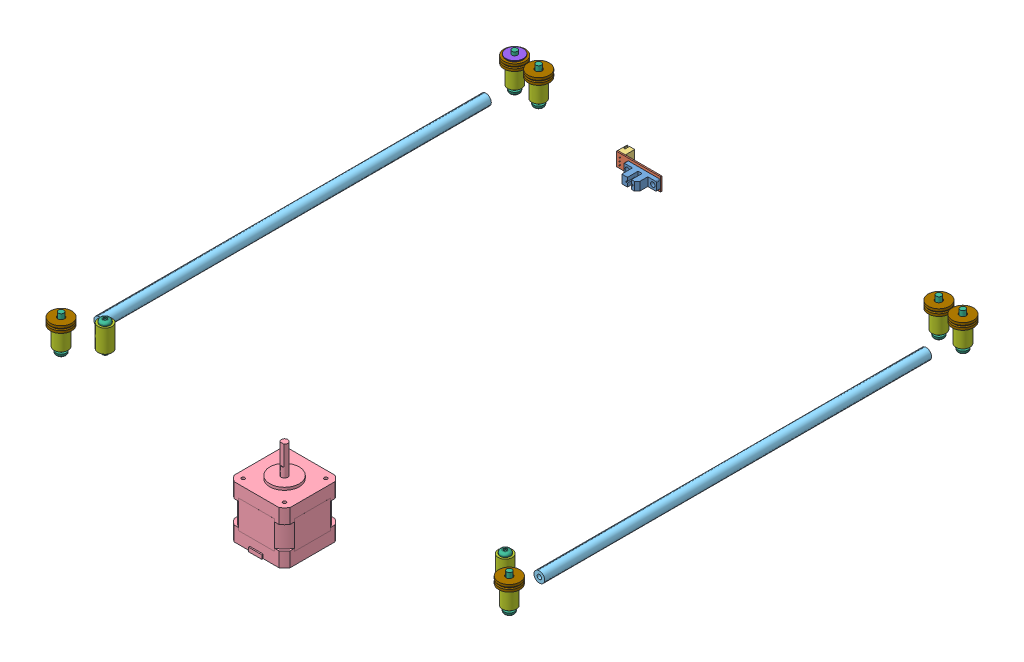
SolidWorks assembly xy motion, configuration Default. Lengths in mm.
Overall size (361.01 63.63 396.4).
41 component instances, 9 part files, 5 mates.
Components (placement in the parent):
- Endstop_Opto_TCST2103-1: Endstop_Opto_TCST2103 [Défaut] at (-96.8686 -36.1328 -195.8999) x (-1 0 0) z (0 0 1) size (33 10 19)
  - TCST2103^Endstop_Opto_TCST2103-1: TCST2103^Endstop_Opto_TCST2103 [Défaut] x (1 0 0) z (0 1 0) size (24.5 11 6.35) (virtual)
  - PCB^Endstop_Opto_TCST2103-1: PCB^Endstop_Opto_TCST2103 [Défaut] x (1 0 0) z (0 0 -1) size (33 10 1) (virtual)
  - Connector^Endstop_Opto_TCST2103-1: Connector^Endstop_Opto_TCST2103 [Défaut] at (0 0 -1) x (1 0 0) z (0 0 -1) size (5.71 10 8.66) (virtual)
- STEPPER-1: STEPPER [Default] at (0 -40.6349 170.5) x (-1 0 0) z (0 1 0) size (42.02 53.01 63.12)
- linear rod-1: linear rod [Default] at (-165 4 -145.5) x (-0.845262 0.534351 0) z (0.534351 0.845262 0) size (8 290 8)
- linear rod-2: linear rod [Default] at (165 4 -145.5) x (-0.273223 -0.961951 0) z (-0.961951 0.273223 0) size (8 290 8)
- M4 PULLEY ASSEMBLY-1: M4 PULLEY ASSEMBLY [Long] at (-168 14 -170) x (0.792146 0 0.610331) z (-0.610331 0 0.792146) size (17.92 27.5 17.92)
  - M4 Screw-1: M4 Screw [M4X25mm] at (0 -16.4994 0) x (0.131421 0 0.991327) z (0.991327 0 -0.131421) size (7.6 27.5 7.6)
  - PULLEY SPACER 1-1: PULLEY SPACER 1 [Long] x (0.779994 0 -0.625787) z (0 -1 0) size (10.5 10.5 14)
  - M4 V-groove pulley-1: M4 V-groove pulley [Default] at origin size (13 6 13) (hidden)
  - V625ZZ-1: V625ZZ [Default] x (0 1 0) z (0.991735 0 -0.128303) size (5 16 16)
- PULLEY SPACER 1-1: PULLEY SPACER 1 [Wire anchor] at (150 17 155) x (-0.096717 0 0.995312) z (0 -1 0) size (10.5 10.5 17)
- M4 PULLEY ASSEMBLY-2: M4 PULLEY ASSEMBLY [Long] at (168 14 -170) x (0.536734 0 -0.843751) z (0.843751 0 0.536734) size (17.92 27.5 17.92)
  - M4 Screw-1: M4 Screw [M4X25mm] at (0 -16.4994 0) x (0.131421 0 0.991327) z (0.991327 0 -0.131421) size (7.6 27.5 7.6)
  - PULLEY SPACER 1-1: PULLEY SPACER 1 [Long] x (0.779994 0 -0.625787) z (0 -1 0) size (10.5 10.5 14)
  - M4 V-groove pulley-1: M4 V-groove pulley [Default] at origin size (13 6 13) (hidden)
  - V625ZZ-1: V625ZZ [Default] x (0 1 0) z (0.991735 0 -0.128303) size (5 16 16)
- M4 Screw-1: M4 Screw [M4X20mm] at (150 17 155) x (0.685414 0 0.728154) z (-0.728154 0 0.685414) size (7.6 22.5 7.6)
- M4 Screw-2: M4 Screw [M4X20mm] at (-150 17 155) x (0.685414 0 0.728154) z (-0.728154 0 0.685414) size (7.6 22.5 7.6)
- M4 PULLEY ASSEMBLY-3: M4 PULLEY ASSEMBLY [Long] at (150 14 -170) x (0.578276 0 0.815841) z (-0.815841 0 0.578276) size (17.92 27.5 17.92)
  - M4 Screw-1: M4 Screw [M4X25mm] at (0 -16.4994 0) x (0.131421 0 0.991327) z (0.991327 0 -0.131421) size (7.6 27.5 7.6)
  - PULLEY SPACER 1-1: PULLEY SPACER 1 [Long] x (0.779994 0 -0.625787) z (0 -1 0) size (10.5 10.5 14)
  - M4 V-groove pulley-1: M4 V-groove pulley [Default] at origin size (13 6 13) (hidden)
  - V625ZZ-1: V625ZZ [Default] x (0 1 0) z (0.991735 0 -0.128303) size (5 16 16)
- M4 PULLEY ASSEMBLY-4: M4 PULLEY ASSEMBLY [Long] at (168 14 170) x (0.536734 0 -0.843751) z (0.843751 0 0.536734) size (17.92 27.5 17.92)
  - M4 Screw-1: M4 Screw [M4X25mm] at (0 -16.4994 0) x (0.131421 0 0.991327) z (0.991327 0 -0.131421) size (7.6 27.5 7.6)
  - PULLEY SPACER 1-1: PULLEY SPACER 1 [Long] x (0.779994 0 -0.625787) z (0 -1 0) size (10.5 10.5 14)
  - M4 V-groove pulley-1: M4 V-groove pulley [Default] at origin size (13 6 13) (hidden)
  - V625ZZ-1: V625ZZ [Default] x (0 1 0) z (0.991735 0 -0.128303) size (5 16 16)
- PULLEY SPACER 1-2: PULLEY SPACER 1 [Wire anchor] at (-150 17 155) x (-0.794649 0 0.607069) z (0 -1 0) size (10.5 10.5 17)
- M4 PULLEY ASSEMBLY-5: M4 PULLEY ASSEMBLY [Long] at (-150 14 -170) x (0.989967 0 -0.141301) z (0.141301 0 0.989967) size (17.92 27.5 17.92)
  - M4 Screw-1: M4 Screw [M4X25mm] at (0 -16.4994 0) x (0.131421 0 0.991327) z (0.991327 0 -0.131421) size (7.6 27.5 7.6)
  - PULLEY SPACER 1-1: PULLEY SPACER 1 [Long] x (0.779994 0 -0.625787) z (0 -1 0) size (10.5 10.5 14)
  - M4 V-groove pulley-1: M4 V-groove pulley [Default] at origin size (13 6 13) (hidden)
  - V625ZZ-1: V625ZZ [Default] x (0 1 0) z (0.991735 0 -0.128303) size (5 16 16)
- M4 PULLEY ASSEMBLY-6: M4 PULLEY ASSEMBLY [Long] at (-168 14 170) x (0.659754 0 0.751482) z (-0.751482 0 0.659754) size (17.92 27.5 17.92)
  - M4 Screw-1: M4 Screw [M4X25mm] at (0 -16.4994 0) x (0.131421 0 0.991327) z (0.991327 0 -0.131421) size (7.6 27.5 7.6)
  - PULLEY SPACER 1-1: PULLEY SPACER 1 [Long] x (0.779994 0 -0.625787) z (0 -1 0) size (10.5 10.5 14)
  - M4 V-groove pulley-1: M4 V-groove pulley [Default] at origin size (13 6 13) (hidden)
  - V625ZZ-1: V625ZZ [Default] x (0 1 0) z (0.991735 0 -0.128303) size (5 16 16)
Mates (geometry in assembly coordinates):
- Coincident18: coincident aligned: plane of linear rod-1 through (-165 4 144.5) normal (0 0 1); plane of linear rod-2 through (165 4 144.5) normal (0 0 1)
- Concentric215: concentric aligned: cylinder of PULLEY SPACER 1-1 through (150 17 155) axis (0 -1 0) radius 2.125; cylinder of M4 Screw-1 through (150 -3 155) axis (0 -1 0) radius 2
- Coincident257: coincident anti-aligned: plane of PULLEY SPACER 1-1 through (149.4922 17 160.2254) normal (0 1 0); plane of M4 Screw-1 through (151.3708 17 156.4563) normal (0 -1 0)
- Concentric214: concentric aligned: cylinder of PULLEY SPACER 1-2 through (-150 17 155) axis (0 -1 0) radius 2.125; cylinder of M4 Screw-2 through (-150 -3 155) axis (0 -1 0) radius 2
- Coincident256: coincident anti-aligned: plane of PULLEY SPACER 1-2 through (-154.1719 17 158.1871) normal (0 1 0); plane of M4 Screw-2 through (-148.6292 17 156.4563) normal (0 -1 0)
